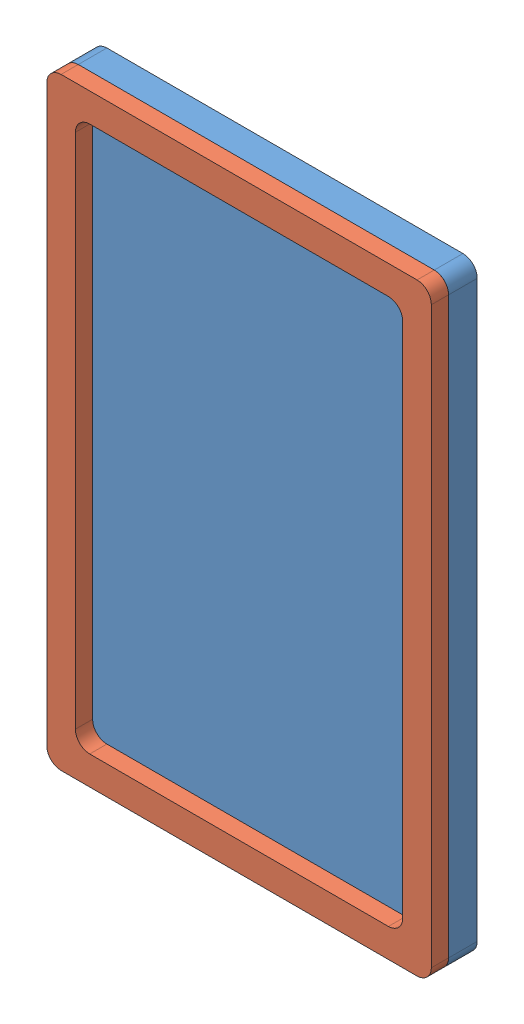
SolidWorks assembly 装配体2, configuration 默认. Lengths in mm.
Overall size (67.16 105.25 8).
2 component instances, 2 part files, 0 mates.
Components (placement in the parent):
- 第一层-1: 第一层 [默认] at origin size (67.16 105.25 5)
- 第二层-1: 第二层 [默认] at (0 0 5) size (67.15 105.25 3)
